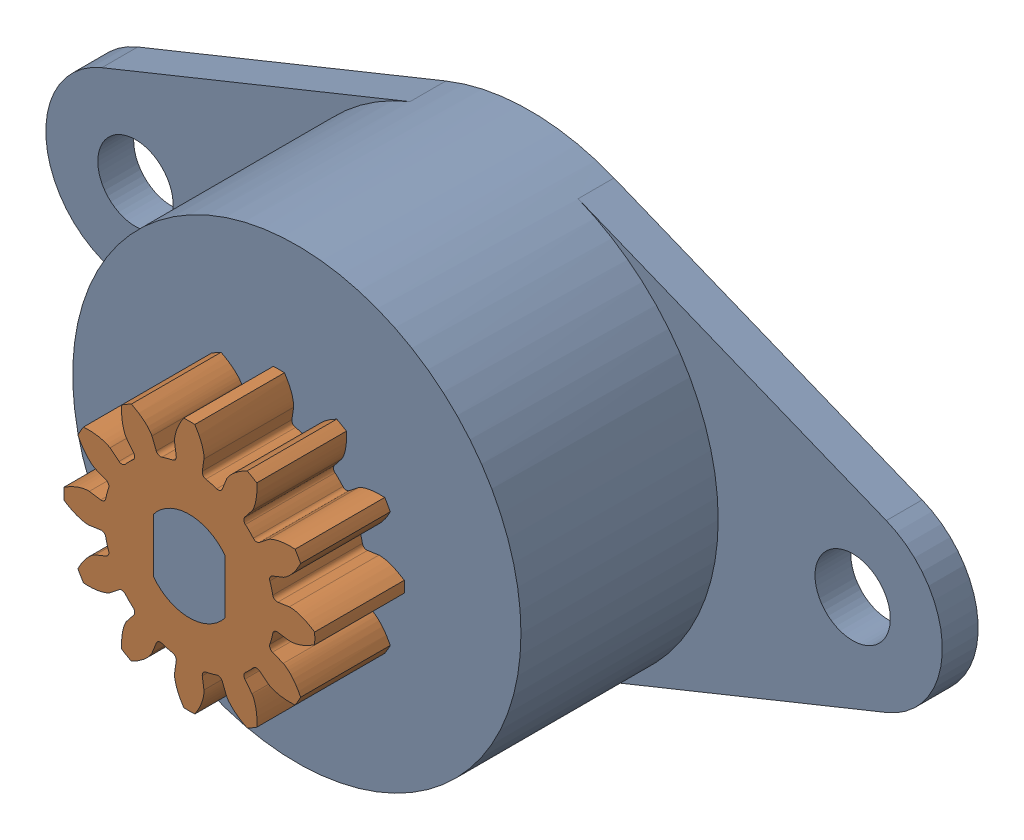
SolidWorks assembly FRT-D2-152-G1, configuration Default. Lengths in mm.
Overall size (50 25 19).
2 component instances, 2 part files, 0 mates.
Components (placement in the parent):
- FRT-D2-152-1: FRT-D2-152 [Default] at origin size (50 25 19)
- FRT-D2-G1 12mm Gear-1: FRT-D2-G1 12mm Gear [Default] at (0 0 14) x (0 -1 0) z (0 0 1) size (14 14 5)
